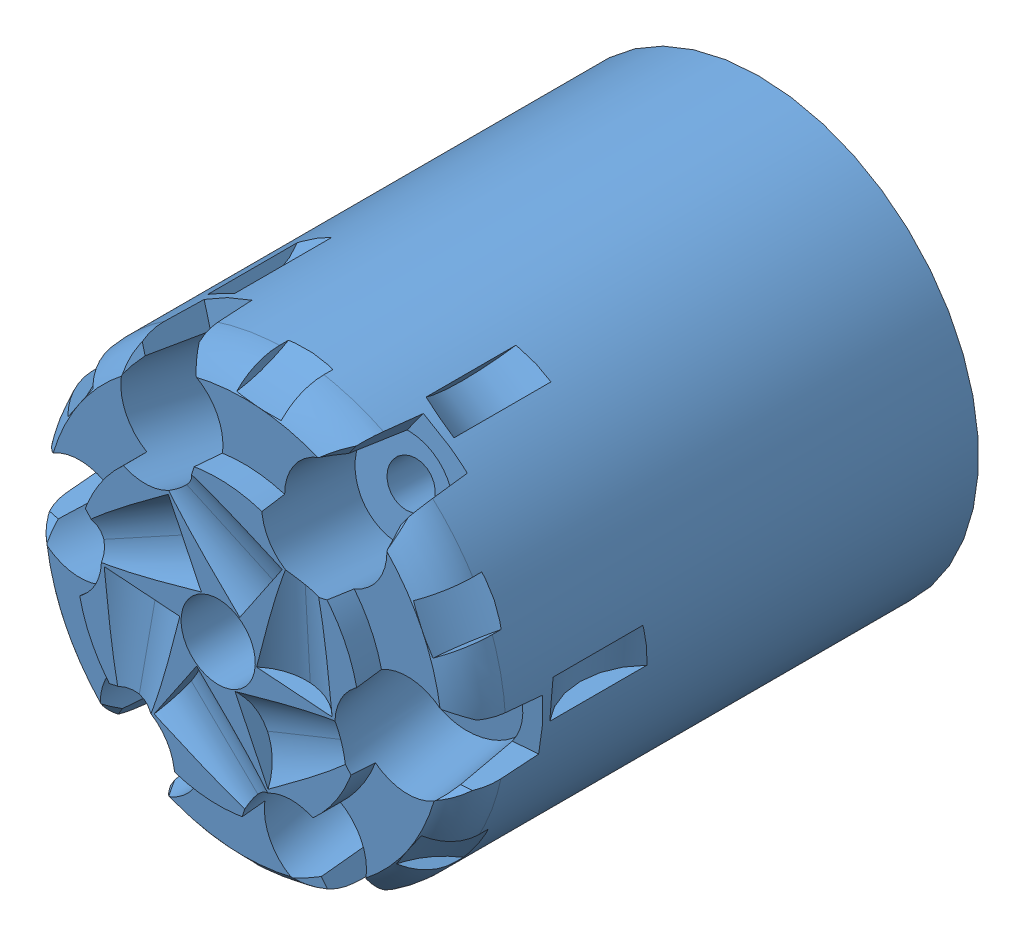
SolidWorks assembly Cylinder.44, configuration Default. Lengths in mm.
Overall size (76.91 85.64 77.53).
4 component instances, 4 part files, 5 mates.
Components (placement in the parent):
- 5mm-1: 5mm [Default] at (0.2237 0.2935 0.3421)
- Cylinder 1858-1: Cylinder 1858 [Default] at (-136.1766 -273.2413 216.2716) x (0.216059 0.319043 -0.922784) z (0.827999 -0.56073 0) size (60.74 55.75 42.2)
- Inner_Cylinder.44-8: Inner_Cylinder.44 [Default] at (12.8911 -0.6159 -1.6496) x (0.966699 -0.255915 0) z (0 0 1) size (11.4 11.4 19.82)
- Piston.44-7: Piston.44 [Default] at (12.8911 -0.6159 29.3504) x (0.969531 0.244967 0) z (0 0 -1) size (9.4 9.4 17)
Mates (geometry in assembly coordinates):
- Concentric1: concentric: circle of 5mm-1; circle of Cylinder 1858-1
- Lock1: lock: unknown of Cylinder 1858-1
- Concentric6: concentric: cylinder of Inner_Cylinder.44-8 through (12.8911 -0.6159 -3.9516) axis (0 0 1) radius 4.7; cylinder of Piston.44-7 through (12.8911 -0.6159 12.3504) axis (0 0 1) radius 4.09
- Coincident3: coincident: plane of Inner_Cylinder.44-8 through (12.8911 -0.6159 29.3504) normal (0 0 1); plane of Piston.44-7 through (12.8911 -0.6159 29.3504) normal (0 0 1)
- Concentric7: concentric: cylinder of Cylinder 1858-1 through (12.8911 -0.6159 15.2083) axis (0 0 -1) radius 5.7; cylinder of Inner_Cylinder.44-8 through (12.8911 -0.6159 29.3504) axis (0 0 -1) radius 5.7
